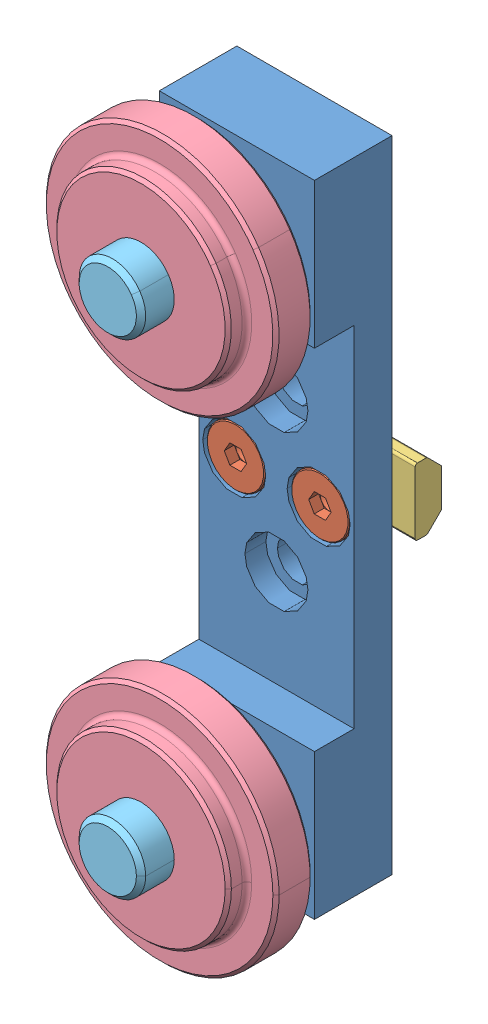
SolidWorks assembly 2018-309-A, configuration Default. Lengths in mm.
Overall size (52.97 124.91 40.56).
16 component instances, 7 part files, 5 mates.
Components (placement in the parent):
- 2752_1-1: 2752_1 [Default] at origin size (28.55 104.78 19.43)
  - _2752_1_b_2-1: _2752_1_b_2 [Default] at origin size (25.4 104.78 12.7)
  - _2750_0_250_4-1: _2750_0_250_4 [Default] at (-6.9088 0 -3.429) x (0 0 -1) z (0 -1 0) size (12.75 9.53 9.53)
  - _3204_6-1: _3204_6 [Default] at (-6.9088 0 -12.7762) x (0 1 0) z (1 0 0) size (10.95 4.34 12.45)
  - _2750_0_250_4-2: _2750_0_250_4 [Default] at (6.9088 0 -3.429) x (0 0 -1) z (0 1 0) size (12.75 9.53 9.53)
  - _3204_6-2: _3204_6 [Default] at (6.9088 0 -12.7762) x (0 -1 0) z (-1 0 0) size (10.95 4.34 12.45)
- 2281-1: 2281 [Default] at (0 39.6875 16.0782) x (0 0 1) z (-0.824809 -0.565411 0) size (29.26 38.1 38.1)
  - _2281_w_2-1: _2281_w_2 [Default] at origin size (12.19 38.1 38.1)
  - _2281_b_4-1: _2281_b_4 [Default] at (6.096 0 0) x (-1 0 0) z (0 0 1) size (29.26 10.9 10.9)
  - _2281_p2_6-1: _2281_p2_6 [Default] at (-8.1026 0 0) size (3 15.8 15.8)
  - _3382_8-1: _3382_8 [Default] at (-13.0048 0 0) x (0 0 -1) z (-1 0 0) size (25.4 11.25 3.15)
- 2281-2: 2281 [Default] at (0 -39.6875 16.0782) x (0 0 1) z (-1 0 0) size (29.26 38.1 38.1)
  - _2281_w_2-1: _2281_w_2 [Default] at origin size (12.19 38.1 38.1)
  - _2281_b_4-1: _2281_b_4 [Default] at (6.096 0 0) x (-1 0 0) z (0 0 1) size (29.26 10.9 10.9)
  - _2281_p2_6-1: _2281_p2_6 [Default] at (-8.1026 0 0) size (3 15.8 15.8)
  - _3382_8-1: _3382_8 [Default] at (-13.0048 0 0) x (0 0 -1) z (-1 0 0) size (25.4 11.25 3.15)
Mates (geometry in assembly coordinates):
- Coincident1: coordinate: point of 2752_1-1/_2752_1_b_2-1
- Concentric1: concentric anti-aligned: cylinder of 2752_1-1/_2752_1_b_2-1 through (0 39.6875 -6.223) axis (0 0 1) radius 2.4879; cylinder of 2281-1/_2281_w_2-1 through (0 39.6875 22.1742) axis (0 0 -1) radius 19.05
- Coincident2: coincident anti-aligned: plane of 2752_1-1/_2752_1_b_2-1 through (12.7 52.3875 6.477) normal (0 0 1); plane of 2281-1/_2281_p2_6-1 through (-4.4664 46.203 6.477) normal (0 0 -1)
- Concentric2: concentric anti-aligned: cylinder of 2752_1-1/_2752_1_b_2-1 through (0 -39.6875 -6.223) axis (0 0 1) radius 2.4879; cylinder of 2281-2/_2281_w_2-1 through (0 -39.6875 22.1742) axis (0 0 -1) radius 19.05
- Coincident3: coincident anti-aligned: plane of 2752_1-1/_2752_1_b_2-1 through (12.7 -28.5877 6.477) normal (0 0 1); plane of 2281-2/_2281_p2_6-1 through (0 -31.7881 6.477) normal (0 0 -1)
